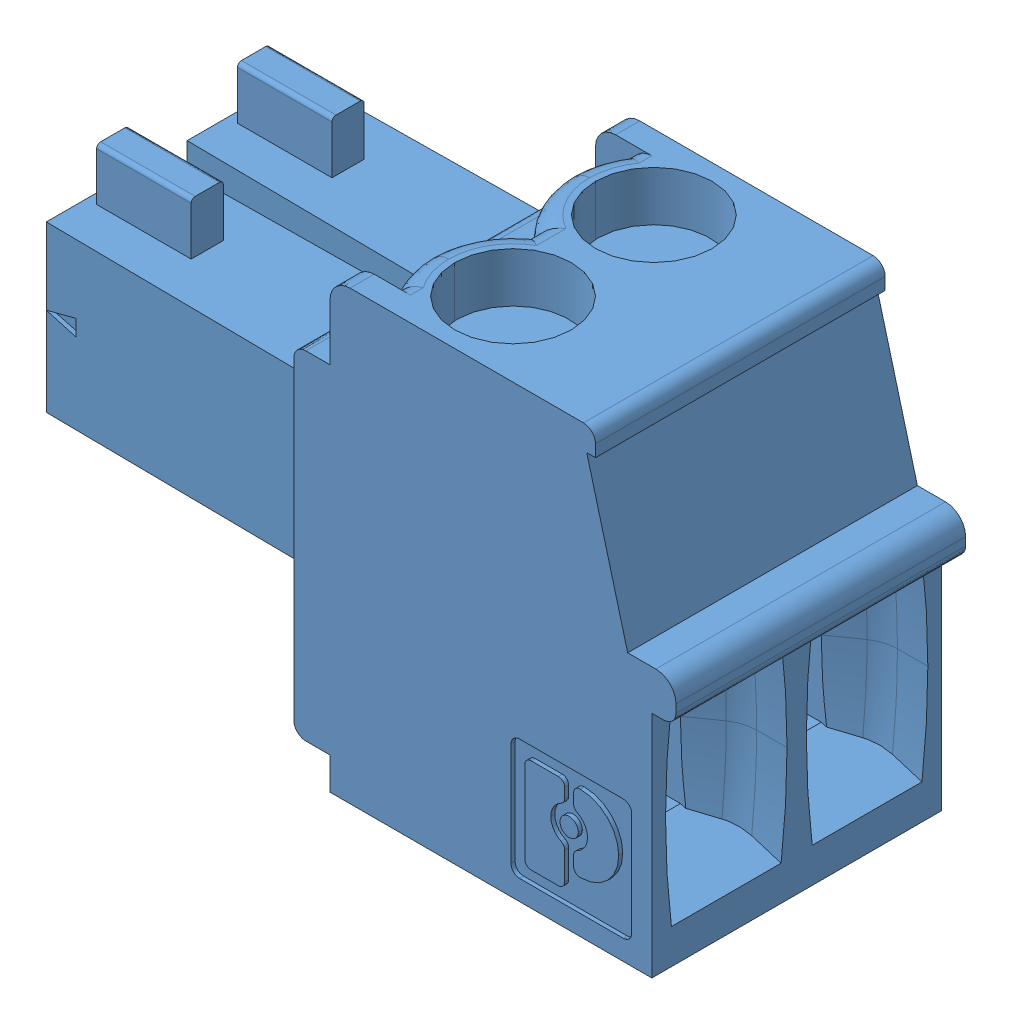
SolidWorks assembly phoenix_2pos_terminal_blk_pxc_1840366_05_MC-1-5-2-ST-3-5_3D, configuration Default. Lengths in mm.
Overall size (16.1 11.1 7.2).
2 component instances, 1 part files, 0 mates.
Components (placement in the parent):
- pxc_1840366_05_MC-1-5-2-ST-3-5_3D.stp-1: pxc_1840366_05_MC-1-5-2-ST-3-5_3D.stp [Default] at origin size (16.1 11.1 7.2)
  - mc_1.5-2-st-3.5.stp-1: mc_1.5-2-st-3.5.stp [Default] at (-42.6111 -29.3822 -77.4049) size (16.1 11.1 7.2)
